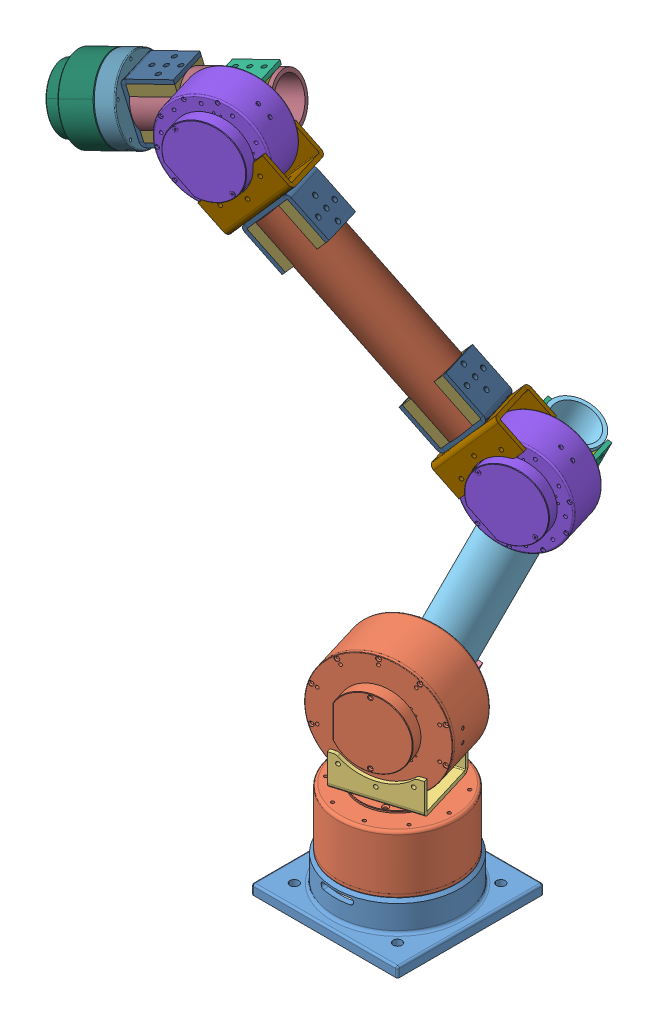
SolidWorks assembly Assembly_P, configuration Default. Lengths in mm.
Overall size (503.69 688.48 209.36).
28 component instances, 15 part files, 90 mates.
Components (placement in the parent):
- base_link_X10-1: base_link_X10 [По умолчанию] at (81.3757 88.1097 90.3224) size (150 40 150)
- RMD-X10-S2-V3-1: RMD-X10-S2-V3 [По умолчанию] at (81.3757 180.7097 90.3224) x (0 0 -1) z (0 -1 0) size (122 122 74)
- corner_p_list_X10-2: corner_p_list_X10 [По умолчанию] at (43.0993 193.6097 101.9378) x (-0.290385 0 -0.95691) z (0.95691 0 -0.290385) size (67 33 80)
- RMD-X10-S2-V3-3: RMD-X10-S2-V3 [По умолчанию] at (74.6678 257.6097 68.2178) x (0.95691 0 -0.290385) z (0.290385 0 0.95691) size (122 122 74)
- corner_p_list__long_X10-1: corner_p_list__long_X10 [По умолчанию] at (79.0579 276.2634 53.4047) x (-0.870726 0.414751 0.264231) z (-0.396879 -0.909935 0.120437) size (58 34 41)
- tube-3: tube [По умолчанию] at (172.804 507.8419 -1.1693) x (-0.396879 -0.909935 0.120437) z (-0.870726 0.414751 0.264231) size (300 50 50)
- corner_p_list__long_X8-2: corner_p_list__long_X8 [По умолчанию] at (178.2777 503.7472 23.2954) x (-0.870726 0.414751 0.264231) z (-0.396879 -0.909935 0.120437) size (58 39 41)
- rubber_pad_for_tube_horizontal-1: rubber_pad_for_tube_horizontal [По умолчанию] at (45.5239 267.9785 50.5181) x (-0.290385 0 -0.95691) z (-0.396879 -0.909935 0.120437) size (25 50 41)
- rubber_pad_for_tube_horizontal-2: rubber_pad_for_tube_horizontal [По умолчанию] at (188.28 474.7247 7.1972) x (-0.290385 0 -0.95691) z (0.396879 0.909935 -0.120437) size (25 50 41)
- RMD-X8-S2-V3-1: RMD-X8-S2-V3 [По умолчанию] at (175.1072 485.0935 42.1275) x (-0.714133 0.66562 0.216711) z (0.290385 0 0.95691) size (98 98 58.1)
- corner_p_list_X8-1: corner_p_list_X8 [По умолчанию] at (115.66 489.8541 71.5583) x (0.290385 0 0.95691) z (0.636938 0.746291 -0.193286) size (51 33 80)
- corner_p_list__long_X8_3_holes-5: corner_p_list__long_X8_3_holes [По умолчанию] at (141.3773 525.0307 85.1772) x (-0.636938 -0.746291 0.193286) z (-0.290385 0 -0.95691) size (58 46.5 41)
- tube_2-1: tube_2 [По умолчанию] at (135.4244 525.0307 65.5605) x (-0.714133 0.66562 0.216711) z (0.636938 0.746291 -0.193286) size (214 50 50)
- corner_p_list__long_X8_3_holes-4: corner_p_list__long_X8_3_holes [По умолчанию] at (-23.353 667.4733 92.3201) x (-0.636938 -0.746291 0.193286) z (0.290385 0 0.95691) size (58 46.5 41)
- corner_p_list_X8-2: corner_p_list_X8 [По умолчанию] at (-48.5907 642.9466 121.4019) x (-0.290385 0 -0.95691) z (0.636938 0.746291 -0.193286) size (51 33 80)
- RMD-X8-S2-V3-2: RMD-X8-S2-V3 [По умолчанию] at (-63.4133 707.4105 114.5091) x (-0.714133 0.66562 0.216711) z (0.290385 0 0.95691) size (98 98 58.1)
- rubber_pad_for_tube_long-1: rubber_pad_for_tube_long [По умолчанию] at (143.3862 534.3593 63.1445) x (-0.636938 -0.746291 0.193286) z (-0.290385 0 -0.95691) size (10.78 42.5 41)
- rubber_pad_for_tube_long-2: rubber_pad_for_tube_long [По умолчанию] at (127.4627 515.702 67.9766) x (0.636938 0.746291 -0.193286) z (0.290385 0 0.95691) size (10.78 42.5 41)
- rubber_pad_for_tube_long-3: rubber_pad_for_tube_long [По умолчанию] at (-9.4384 676.802 109.5207) x (-0.636938 -0.746291 0.193286) z (0.290385 0 0.95691) size (10.78 42.5 41)
- rubber_pad_for_tube_long-5: rubber_pad_for_tube_long [По умолчанию] at (-25.3618 658.1447 114.3528) x (0.636938 0.746291 -0.193286) z (-0.290385 0 -0.95691) size (10.78 42.5 41)
- tube_3-1: tube_3 [По умолчанию] at (-52.8417 714.9899 67.3053) x (-0.911873 -0.303175 0.276718) z (-0.290111 0.952935 0.088037) size (122 50 50)
- corner_p_list__long_X8-5: corner_p_list__long_X8 [По умолчанию] at (-49.6855 713.6256 92.4733) x (-0.290111 0.952935 0.088037) z (-0.911873 -0.303175 0.276718) size (58 39 41)
- X6_fixator-1: X6_fixator [По умолчанию] at (-184.1514 671.3327 107.1526) x (-0.106425 -0.476468 -0.872727) z (0.911873 0.303175 -0.276718) size (76 76 18)
- RMD-X6-S2-V2.step-1: RMD-X6-S2-V2.step [По умолчанию] at (-128.7935 114.9401 -204.3735) x (0.106425 0.476468 0.872727) z (-0.911873 -0.303175 0.276718) size (76 76 63)
- rubber_pad_for_tube_horizontal-3: rubber_pad_for_tube_horizontal [По умолчанию] at (-64.7559 683.5871 83.9837) x (-0.290385 0 -0.95691) z (0.911873 0.303175 -0.276718) size (25 50 41)
- corner_p_list__long_X8_3_holes-6: corner_p_list__long_X8_3_holes [По умолчанию] at (-170.0431 678.0026 81.4482) x (0.290111 -0.952935 -0.088037) z (0.290385 0 0.95691) size (58 46.5 41)
- rubber_pad_for_tube_long-6: rubber_pad_for_tube_long [По умолчанию] at (-160.4638 666.0909 99.9644) x (-0.290111 0.952935 0.088037) z (-0.290385 0 -0.95691) size (10.78 42.5 41)
- rubber_pad_for_tube_long-7: rubber_pad_for_tube_long [По умолчанию] at (-167.7166 689.9143 102.1653) x (0.290111 -0.952935 -0.088037) z (0.290385 0 0.95691) size (10.78 42.5 41)
Mates (geometry in assembly coordinates):
- Концентричный1: concentric: circle of First link-1; circle of RMD-X10-S2-V3-1
- Концентричный2: concentric: circle of First link-1; circle of RMD-X10-S2-V3-1
- Совпадение1: coincident: plane of First link-1 through (81.3757 128.1097 90.3224) normal (0 1 0); plane of RMD-X10-S2-V3-1 through (141.3757 128.1097 90.3224) normal (0 -1 0)
- Концентричный5: concentric: circle of RMD-X10-S2-V3-1; circle of corner_p_list_X10-2
- Совпадение2: coincident: plane of RMD-X10-S2-V3-1 through (81.3757 189.6097 90.3224) normal (0 1 0); plane of corner_p_list_X10-2 through (128.2184 189.6097 106.9359) normal (0 -1 0)
- Концентричный6: concentric: circle of corner_p_list_X10-2; circle of RMD-X10-S2-V3-3
- Концентричный7: concentric: circle of corner_p_list_X10-2; circle of RMD-X10-S2-V3-3
- Совпадение3: coincident: plane of corner_p_list_X10-2 through (128.2184 193.6097 106.9359) normal (-0.290385 0 -0.95691); plane of RMD-X10-S2-V3-3 through (89.942 317.6097 118.5513) normal (0.290385 0 0.95691)
- Концентричный8: concentric: circle of RMD-X10-S2-V3-3; circle of corner_p_list_X10_TEST-1
- Совпадение4: coincident: plane of RMD-X10-S2-V3-3 through (72.0834 257.6097 59.7013) normal (-0.290385 0 -0.95691); plane of corner_p_list__long_X10-1 through (85.7155 228.5873 55.5645) normal (0.290385 0 0.95691)
- Концентричный12: concentric: cylinder of corner_p_list__long_X10-1 through (83.9523 234.2078 25.7937) axis (-0.870726 0.414751 0.264231) radius 2.5; cylinder of tube-3 through (28.2258 260.7518 42.7045) axis (0.870726 -0.414751 -0.264231) radius 2.5
- Концентричный13: concentric: cylinder of corner_p_list__long_X10-1 through (88.9133 245.582 24.2882) axis (-0.870726 0.414751 0.264231) radius 2.5; cylinder of tube-3 through (33.1868 272.126 41.199) axis (0.870726 -0.414751 -0.264231) radius 2.5
- Концентричный14: concentric: cylinder of corner_p_list__long_X10-1 through (83.9523 234.2078 25.7937) axis (-0.870726 0.414751 0.264231) radius 2.5; cylinder of tube-3 through (28.2258 260.7518 42.7045) axis (0.870726 -0.414751 -0.264231) radius 2.5
- Касательность3: tangent: plane of corner_p_list__long_X10-1 through (41.0177 249.3249 64.9484) normal (0.870726 -0.414751 -0.264231); cylinder of tube-3 through (53.7402 234.8614 34.9619) axis (0.396879 0.909935 -0.120437) radius 25
- Концентричный15: concentric: cylinder of tube-3 through (132.4066 499.6098 11.0897) axis (0.870726 -0.414751 -0.264231) radius 2.5; cylinder of corner_p_list__long_X8-2 through (188.1331 473.0657 -5.8211) axis (-0.870726 0.414751 0.264231) radius 2.5
- Концентричный16: concentric: cylinder of tube-3 through (137.3676 510.984 9.5842) axis (0.870726 -0.414751 -0.264231) radius 2.5; cylinder of corner_p_list__long_X8-2 through (193.0941 484.4399 -7.3266) axis (-0.870726 0.414751 0.264231) radius 2.5
- Касательность4: tangent: cylinder of tube-3 through (53.7402 234.8614 34.9619) axis (0.396879 0.909935 -0.120437) radius 25; plane of corner_p_list__long_X8-2 through (183.7738 456.0711 21.6276) normal (-0.870726 0.414751 0.264231)
- Концентричный17: concentric: cone of RMD-X8-S2-V3-1 through (171.3032 485.0935 29.592) axis (-0.290385 0 -0.95691); circle of corner_p_list__long_X10-2
- Совпадение5: coincident: plane of corner_p_list__long_X8-2 through (184.9353 456.0711 25.4552) normal (0.290385 0 0.95691); plane of RMD-X8-S2-V3-1 through (171.3032 485.0935 29.592) normal (-0.290385 0 -0.95691)
- Концентричный20: concentric: cylinder of corner_p_list__long_X8_3_holes-5 through (109.5747 553.3195 89.6029) axis (0.714133 -0.66562 -0.216711) radius 2; cylinder of corner_p_list_X8-1 through (166.3483 500.4028 72.3743) axis (-0.714133 0.66562 0.216711) radius 2
- Концентричный21: concentric: cylinder of corner_p_list_X8-1 through (155.548 490.385 67.5528) axis (-0.714133 0.66562 0.216711) radius 2; cylinder of corner_p_list__long_X8_3_holes-5 through (98.7744 543.3018 84.7814) axis (0.714133 -0.66562 -0.216711) radius 2
- Совпадение7: coincident: plane of corner_p_list_X8-1 through (157.5152 552.2198 36.3887) normal (-0.714133 0.66562 0.216711); plane of corner_p_list__long_X8_3_holes-5 through (148.2515 541.0255 40.2449) normal (0.714133 -0.66562 -0.216711)
- Концентричный24: concentric: cylinder of corner_p_list__long_X8_3_holes-5 through (144.969 554.9934 62.6641) axis (-0.636938 -0.746291 0.193286) radius 2.5; cylinder of tube_2-1 through (148.7906 559.4711 61.5044) axis (-0.636938 -0.746291 0.193286) radius 2.5
- Концентричный25: concentric: cylinder of corner_p_list__long_X8_3_holes-5 through (136.0423 563.3136 65.373) axis (-0.636938 -0.746291 0.193286) radius 2.5; cylinder of tube_2-1 through (139.8639 567.7914 64.2133) axis (-0.636938 -0.746291 0.193286) radius 2.5
- Касательность6: tangent: plane of corner_p_list__long_X8_3_holes-5 through (145.395 543.688 41.1117) normal (-0.636938 -0.746291 0.193286); cylinder of tube_2-1 through (-17.4001 667.4733 111.9368) axis (0.714133 -0.66562 -0.216711) radius 25
- Концентричный26: concentric: cylinder of tube_2-1 through (22.7461 676.953 99.754) axis (-0.636938 -0.746291 0.193286) radius 2.5; cylinder of corner_p_list__long_X8_3_holes-4 through (18.9244 672.4753 100.9137) axis (-0.636938 -0.746291 0.193286) radius 2.5
- Концентричный27: concentric: cylinder of tube_2-1 through (13.8194 685.2733 102.4629) axis (-0.636938 -0.746291 0.193286) radius 2.5; cylinder of corner_p_list__long_X8_3_holes-4 through (9.9978 680.7955 103.6226) axis (-0.636938 -0.746291 0.193286) radius 2.5
- Касательность7: tangent: cylinder of tube_2-1 through (-17.4001 667.4733 111.9368) axis (0.714133 -0.66562 -0.216711) radius 25; plane of corner_p_list__long_X8_3_holes-4 through (-27.3707 648.816 136.3856) normal (0.636938 0.746291 -0.193286)
- Концентричный28: concentric: cylinder of corner_p_list_X8-2 through (-39.3221 692.1012 134.7872) axis (0.714133 -0.66562 -0.216711) radius 2; cylinder of corner_p_list__long_X8_3_holes-4 through (17.4515 639.1845 117.5586) axis (-0.714133 0.66562 0.216711) radius 2
- Концентричный29: concentric: cylinder of corner_p_list__long_X8_3_holes-4 through (6.6512 629.1667 112.7371) axis (-0.714133 0.66562 0.216711) radius 2; cylinder of corner_p_list_X8-2 through (-50.1224 682.0835 129.9657) axis (0.714133 -0.66562 -0.216711) radius 2
- Совпадение8: coincident: plane of corner_p_list__long_X8_3_holes-4 through (1.6197 688.7931 127.5881) normal (-0.714133 0.66562 0.216711); plane of corner_p_list_X8-2 through (11.4641 699.9874 125.6457) normal (0.714133 -0.66562 -0.216711)
- Концентричный33: concentric: circle of RMD-X8-S2-V3-2; circle of corner_p_list__long_X10-5
- Совпадение10: coincident: plane of RMD-X8-S2-V3-2 through (-67.2174 707.4105 101.9736) normal (-0.290385 0 -0.95691); plane of corner_p_list__long_X8-5 through (-78.658 677.372 105.4454) normal (0.290385 0 0.95691)
- Концентричный34: concentric: cylinder of tube_3-1 through (-74.394 744.5529 73.8456) axis (0.290111 -0.952935 -0.088037) radius 2.5; cylinder of corner_p_list__long_X8-5 through (-55.8269 683.5651 68.2112) axis (-0.290111 0.952935 0.088037) radius 2.5
- Концентричный35: concentric: cylinder of tube_3-1 through (-85.7924 740.7632 77.3045) axis (0.290111 -0.952935 -0.088037) radius 2.5; cylinder of corner_p_list__long_X8-5 through (-67.2253 679.7754 71.6701) axis (-0.290111 0.952935 0.088037) radius 2.5
- Касательность10: tangent: cylinder of tube_3-1 through (-164.0902 678.0026 101.0648) axis (0.911873 0.303175 -0.276718) radius 25; plane of corner_p_list__long_X8-5 through (-79.8195 677.372 101.6177) normal (-0.290111 0.952935 0.088037)
- Концентричный36: concentric anti-aligned: cylinder of tube_3-1 through (-162.8457 715.145 100.6872) axis (0.290111 -0.952935 -0.088037) radius 2.5; cylinder of corner_p_list__long_X10-6 through (136.3698 759.8215 42.2327) axis (-0.021041 0.987856 -0.153942) radius 2.5
- Концентричный37: concentric anti-aligned: cylinder of tube_3-1 through (-151.4472 718.9347 97.2282) axis (0.290111 -0.952935 -0.088037) radius 2.5; cylinder of corner_p_list__long_X10-6 through (138.0421 761.7637 54.4672) axis (-0.021041 0.987856 -0.153942) radius 2.5
- Касательность11: tangent anti-aligned: cylinder of tube_3-1 through (-164.0902 678.0026 101.0648) axis (0.911873 0.303175 -0.276718) radius 25; plane of corner_p_list__long_X10-6 through (153.8725 811.2236 18.9092) normal (0.021041 -0.987856 0.153942)
- Концентричный38: concentric: cylinder of corner_p_list_X8-2 through (-59.1117 666.3699 97.9463) axis (0.290385 0 0.95691) radius 2; cylinder of RMD-X8-S2-V3-2 through (-45.4636 666.3699 142.9211) axis (0.290385 0 0.95691) radius 1.65
- Концентричный39: concentric: cylinder of corner_p_list_X8-2 through (-27.6635 703.2173 88.403) axis (0.290385 0 0.95691) radius 2; cylinder of RMD-X8-S2-V3-2 through (-14.0154 703.2173 133.3778) axis (0.290385 0 0.95691) radius 1.65
- Совпадение11: coincident: plane of corner_p_list_X8-2 through (8.6076 702.6499 126.5126) normal (-0.290385 0 -0.95691); plane of RMD-X8-S2-V3-2 through (-38.651 693.0997 140.8537) normal (0.290385 0 0.95691)
- Концентричный48: concentric anti-aligned: cylinder of corner_p_list__long_X10-6 through (138.4795 773.407 57.6676) axis (-0.133779 -0.155373 -0.978756) radius 2.5; cylinder of X6_fixator-1 through (-179.6514 671.3324 121.985) axis (0.911873 0.303175 -0.276718) radius 2
- Концентричный49: concentric anti-aligned: cylinder of corner_p_list__long_X10-6 through (122.8453 782.2977 58.3932) axis (-0.133779 -0.155373 -0.978756) radius 2.5; cylinder of X6_fixator-1 through (-185.7961 684.124 115.7507) axis (0.911873 0.303175 -0.276718) radius 2
- Совпадение18: coincident anti-aligned: plane of corner_p_list__long_X10-6 through (154.3895 761.2093 22.6913) normal (-0.133779 -0.155373 -0.978756); plane of X6_fixator-1 through (-167.7377 676.7899 102.1717) normal (0.911873 0.303175 -0.276718)
- Концентричный51: concentric: cylinder of X6_fixator-1 through (-174.2885 638.9326 104.1596) axis (0.911873 0.303175 -0.276718) radius 1.5; cylinder of RMD-X6-S2-V2.step-1 through (-174.2876 638.9329 104.1593) axis (-0.911873 -0.303175 0.276718) radius 1.25
- Концентричный52: concentric: cylinder of X6_fixator-1 through (-170.6701 655.1325 133.8323) axis (0.911873 0.303175 -0.276718) radius 1.5; cylinder of RMD-X6-S2-V2.step-1 through (-170.6692 655.1328 133.8321) axis (-0.911873 -0.303175 0.276718) radius 1.25
- Совпадение19: coincident: plane of X6_fixator-1 through (-184.1514 671.3327 107.1526) normal (-0.911873 -0.303175 0.276718); plane of RMD-X6-S2-V2.step-1 through (-195.8463 695.6781 95.2873) normal (0.911873 0.303175 -0.276718)
- Совпадение22: coincident: line of corner_p_list__long_X10-1 through (100.5356 265.8946 45.842) axis (-0.290385 0 -0.95691); line of rubber_pad_for_tube_horizontal-1 through (93.5664 265.8946 22.8762) axis (0.290385 0 0.95691)
- Совпадение23: coincident: plane of corner_p_list__long_X10-1 through (84.554 228.5873 51.7369) normal (-0.870726 0.414751 0.264231); plane of rubber_pad_for_tube_horizontal-1 through (89.0602 247.241 37.3065) normal (0.870726 -0.414751 -0.264231)
- Концентричный53: concentric: cylinder of tube-3 through (53.7402 234.8614 34.9619) axis (0.396879 0.909935 -0.120437) radius 25; circle of rubber_pad_for_tube_horizontal-1
- Совпадение24: coincident: line of corner_p_list__long_X8-2 through (199.7554 493.3784 15.7327) axis (-0.290385 0 -0.95691); line of rubber_pad_for_tube_horizontal-2 through (199.7554 493.3784 15.7327) axis (-0.290385 0 -0.95691)
- Параллельность1: parallel: line of corner_p_list__long_X8-2 through (130.074 476.8086 1.3473) axis (0.396879 0.909935 -0.120437); line of rubber_pad_for_tube_horizontal-2 through (149.2935 514.0952 5.9652) axis (-0.396879 -0.909935 0.120437)
- Совпадение26: coincident: plane of corner_p_list__long_X8-2 through (183.7738 456.0711 21.6276) normal (-0.870726 0.414751 0.264231); plane of rubber_pad_for_tube_horizontal-2 through (188.28 474.7247 7.1972) normal (0.870726 -0.414751 -0.264231)
- Совпадение27: coincident: plane of corner_p_list__long_X8-2 through (183.7738 456.0711 21.6276) normal (-0.290385 0 -0.95691); plane of rubber_pad_for_tube_horizontal-2 through (156.5095 514.1159 29.9012) normal (0.290385 0 0.95691)
- Совпадение57: coincident: line of corner_p_list__long_X8-5 through (-67.1017 737.449 61.1823) axis (0.290385 0 0.95691); line of rubber_pad_for_tube_horizontal-3 through (-57.2286 737.449 93.7173) axis (-0.290385 0 -0.95691)
- Совпадение58: coincident: plane of corner_p_list__long_X8-5 through (-79.8195 677.372 101.6177) normal (-0.290385 0 -0.95691); plane of rubber_pad_for_tube_horizontal-3 through (-56.9383 737.449 94.6742) normal (0.290385 0 0.95691)
- Совпадение59: coincident: line of corner_p_list__long_X8-5 through (-56.6482 736.496 94.5862) axis (0.290111 -0.952935 -0.088037); line of rubber_pad_for_tube_horizontal-3 through (-56.6482 736.496 94.5862) axis (0.290111 -0.952935 -0.088037)
- Совпадение65: coincident aligned: line of corner_p_list__long_X10-6 through (159.0221 762.5406 56.5848) axis (-0.021041 0.987856 -0.153942); line of rubber_pad_for_tube-6 through (158.9379 766.492 55.969) axis (-0.021041 0.987856 -0.153942)
- Совпадение66: coincident anti-aligned: line of corner_p_list__long_X10-6 through (155.0584 761.9861 27.5851) axis (0.133779 0.155373 0.978756); line of rubber_pad_for_tube-6 through (158.9379 766.492 55.969) axis (-0.133779 -0.155373 -0.978756)
- Совпадение67: coincident aligned: line of corner_p_list__long_X10-6 through (157.8859 815.8848 48.2719) axis (-0.021041 0.987856 -0.153942); line of rubber_pad_for_tube-7 through (158.1127 805.2372 49.9312) axis (-0.021041 0.987856 -0.153942)
- Совпадение68: coincident anti-aligned: plane of corner_p_list__long_X10-6 through (153.8725 811.2236 18.9092) normal (0.021041 -0.987856 0.153942); plane of rubber_pad_for_tube-7 through (117.2636 815.8848 53.8243) normal (-0.021041 0.987856 -0.153942)
- Совпадение69: coincident aligned: line of corner_p_list__long_X10-6 through (157.8859 815.8848 48.2719) axis (-0.990788 0 0.135423); line of rubber_pad_for_tube-7 through (157.8859 815.8848 48.2719) axis (-0.990788 0 0.135423)
- Совпадение70: coincident: line of assembly; line of assembly; line of corner_p_list__long_X8_3_holes-5 through (115.0443 571.9768 50.322) axis (0.290385 0 0.95691); moEndPointRef_w of ?; line of rubber_pad_for_tube_long-1 through (126.9501 571.9768 89.5553) axis (-0.290385 0 -0.95691)
- Совпадение71: coincident: plane of corner_p_list__long_X8_3_holes-5 through (145.395 543.688 41.1117) normal (-0.636938 -0.746291 0.193286); plane of rubber_pad_for_tube_long-1 through (115.0443 571.9768 50.322) normal (0.636938 0.746291 -0.193286)
- Совпадение72: coincident: line of corner_p_list__long_X8_3_holes-5 through (156.5866 544.3536 80.5618) axis (-0.714133 0.66562 0.216711); line of rubber_pad_for_tube_long-1 through (126.9501 571.9768 89.5553) axis (0.714133 -0.66562 -0.216711)
- Совпадение73: coincident: line of corner_p_list__long_X8_3_holes-5 through (83.1974 534.6622 59.9863) axis (0.290385 0 0.95691); line of rubber_pad_for_tube_long-2 through (83.1974 534.6622 59.9863) axis (0.290385 0 0.95691)
- Совпадение74: coincident: plane of corner_p_list__long_X8_3_holes-5 through (113.5481 506.3734 50.776) normal (0.636938 0.746291 -0.193286); plane of rubber_pad_for_tube_long-2 through (95.1032 534.6622 99.2196) normal (-0.636938 -0.746291 0.193286)
- Совпадение75: coincident: line of corner_p_list__long_X8_3_holes-5 through (95.1032 534.6622 99.2196) axis (0.714133 -0.66562 -0.216711); line of rubber_pad_for_tube_long-2 through (95.1032 534.6622 99.2196) axis (0.714133 -0.66562 -0.216711)
- Совпадение77: coincident: line of corner_p_list__long_X8_3_holes-4 through (5.1904 685.465 126.5046) axis (0.714133 -0.66562 -0.216711); line of rubber_pad_for_tube_long-3 through (34.8269 657.8418 117.511) axis (-0.714133 0.66562 0.216711)
- Совпадение78: coincident: plane of corner_p_list__long_X8_3_holes-4 through (4.4762 686.1306 126.7213) normal (0.714133 -0.66562 -0.216711); plane of rubber_pad_for_tube_long-3 through (-9.4384 676.802 109.5207) normal (-0.714133 0.66562 0.216711)
- Совпадение79: coincident: line of corner_p_list__long_X8_3_holes-4 through (-6.7154 685.465 87.2713) axis (0.714133 -0.66562 -0.216711); line of rubber_pad_for_tube_long-3 through (22.9211 657.8418 78.2777) axis (-0.714133 0.66562 0.216711)
- Совпадение80: coincident: line of corner_p_list__long_X8_3_holes-4 through (2.98 620.5272 127.1753) axis (-0.714133 0.66562 0.216711); line of rubber_pad_for_tube_long-5 through (2.98 620.5272 127.1753) axis (-0.714133 0.66562 0.216711)
- Совпадение81: coincident: line of corner_p_list__long_X8_3_holes-4 through (-8.9258 620.5272 87.942) axis (-0.714133 0.66562 0.216711); line of rubber_pad_for_tube_long-5 through (-8.9258 620.5272 87.942) axis (-0.714133 0.66562 0.216711)
- Совпадение82: coincident: line of corner_p_list__long_X8_3_holes-4 through (2.98 620.5272 127.1753) axis (-0.290385 0 -0.95691); line of rubber_pad_for_tube_long-5 through (2.98 620.5272 127.1753) axis (-0.290385 0 -0.95691)
- Концентричный54: concentric: cylinder of tube_3-1 through (-140.0488 722.7243 93.7692) axis (0.290111 -0.952935 -0.088037) radius 2.5; cylinder of corner_p_list__long_X8_3_holes-6 through (-138.3082 717.0067 93.241) axis (0.290111 -0.952935 -0.088037) radius 2.5
- Концентричный55: concentric: cylinder of tube_3-1 through (-151.4472 718.9347 97.2282) axis (0.290111 -0.952935 -0.088037) radius 2.5; cylinder of corner_p_list__long_X8_3_holes-6 through (-149.7066 713.217 96.7) axis (0.290111 -0.952935 -0.088037) radius 2.5
- Касательность12: tangent: cylinder of tube_3-1 through (-164.0902 678.0026 101.0648) axis (0.911873 0.303175 -0.276718) radius 25; plane of corner_p_list__long_X8_3_holes-6 through (-165.3901 701.8259 122.8824) normal (0.290111 -0.952935 -0.088037)
- Концентричный56: concentric: circle of X6_fixator-1; circle of corner_p_list__long_X8_3_holes-6
- Концентричный57: concentric: circle of X6_fixator-1; circle of corner_p_list__long_X8_3_holes-6
- Совпадение86: coincident: plane of X6_fixator-1 through (-167.7377 676.7899 102.1717) normal (0.911873 0.303175 -0.276718); plane of corner_p_list__long_X8_3_holes-6 through (-169.0376 700.6132 123.9893) normal (-0.911873 -0.303175 0.276718)
- Концентричный58: concentric: cylinder of tube_3-1 through (-164.0902 678.0026 101.0648) axis (0.911873 0.303175 -0.276718) radius 25; cylinder of rubber_pad_for_tube_long-6 through (-164.0902 678.0026 101.0648) axis (0.911873 0.303175 -0.276718) radius 24.95
- Совпадение87: coincident: plane of corner_p_list__long_X8_3_holes-6 through (-150.8845 654.1792 118.4806) normal (-0.290111 0.952935 0.088037); plane of rubber_pad_for_tube_long-6 through (-124.0357 667.0641 67.4867) normal (0.290111 -0.952935 -0.088037)
- Совпадение88: coincident: cylinder of corner_p_list__long_X8_3_holes-6 through (-138.3082 717.0067 93.241) axis (0.290111 -0.952935 -0.088037) radius 2.5; circle of rubber_pad_for_tube_long-6
- Концентричный59: concentric: cylinder of tube_3-1 through (-164.0902 678.0026 101.0648) axis (0.911873 0.303175 -0.276718) radius 25; cylinder of rubber_pad_for_tube_long-7 through (-164.0902 678.0026 101.0648) axis (0.911873 0.303175 -0.276718) radius 24.95
- Совпадение89: coincident: plane of corner_p_list__long_X8_3_holes-6 through (-165.3901 701.8259 122.8824) normal (0.290111 -0.952935 -0.088037); plane of rubber_pad_for_tube_long-7 through (-126.6355 714.7109 111.1219) normal (-0.290111 0.952935 0.088037)
- Совпадение91: coincident: cylinder of corner_p_list__long_X8_3_holes-6 through (-138.3082 717.0067 93.241) axis (0.290111 -0.952935 -0.088037) radius 2.5; circle of rubber_pad_for_tube_long-7
- Концентричный60: concentric: cylinder of RMD-X8-S2-V3-1 through (144.5263 489.2867 85.2666) axis (0.290385 0 0.95691) radius 1.65; circle of corner_p_list_X8-1
- Концентричный61: concentric: circle of RMD-X8-S2-V3-1; circle of corner_p_list_X8-1
- Совпадение93: coincident: plane of RMD-X8-S2-V3-1 through (199.8696 470.7827 68.4721) normal (0.290385 0 0.95691); plane of corner_p_list_X8-1 through (172.8583 549.5574 76.669) normal (-0.290385 0 -0.95691)
